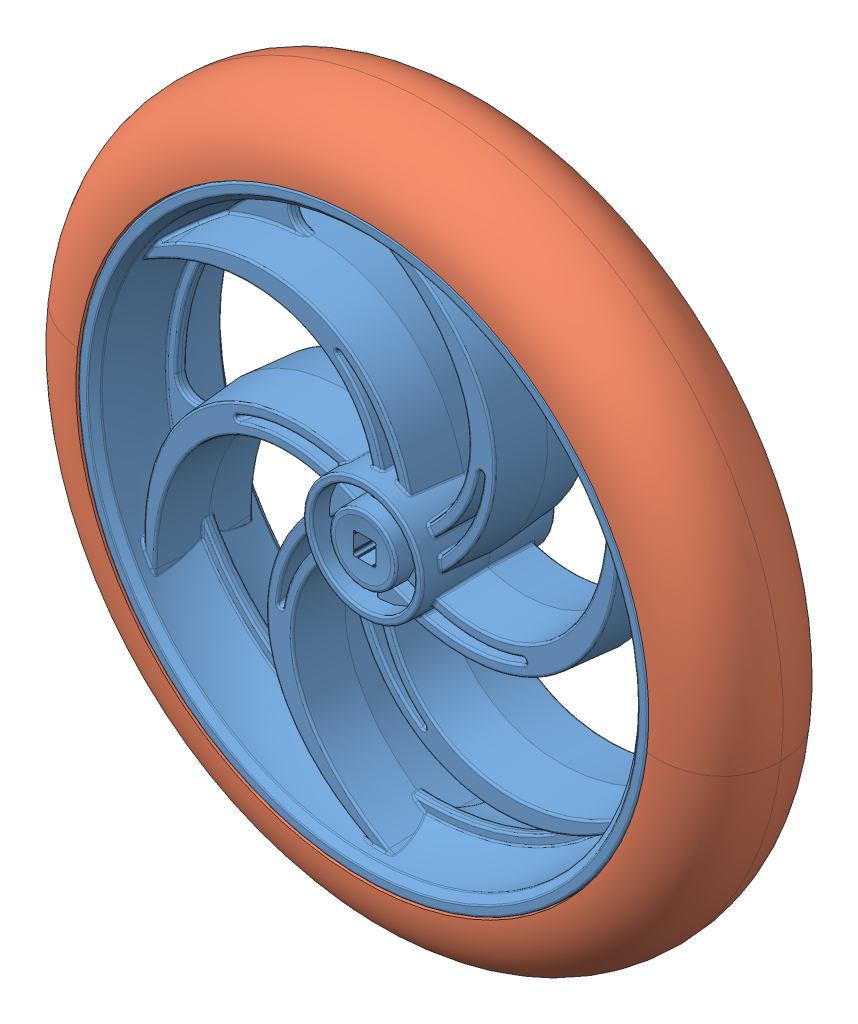
SolidWorks assembly 4in HighTraction, configuration Default. Lengths in mm.
Overall size (112.59 112.59 19.15).
2 component instances, 2 part files, 1 mates.
Components (placement in the parent):
- MEDIUM-WHEEL-HUB-1: MEDIUM-WHEEL-HUB [Default] at (-6.9406 43.8687 -26.1403) size (92.9 92.77 19.05)
- WHEEL___-1: WHEEL___ [Default] at (-6.9406 43.8687 -26.1403) x (0.99343 -0.114443 0) z (0 0 1) size (101.63 101.63 19.15)
Mates (geometry in assembly coordinates):
- Coincident1: coincident: cone of MEDIUM-WHEEL-HUB-1 through (-6.9406 43.8687 -32.1802) axis (0 0 -1); cone of WHEEL___-1 through (-6.9406 43.8687 -32.1802) axis (0 0 -1)
